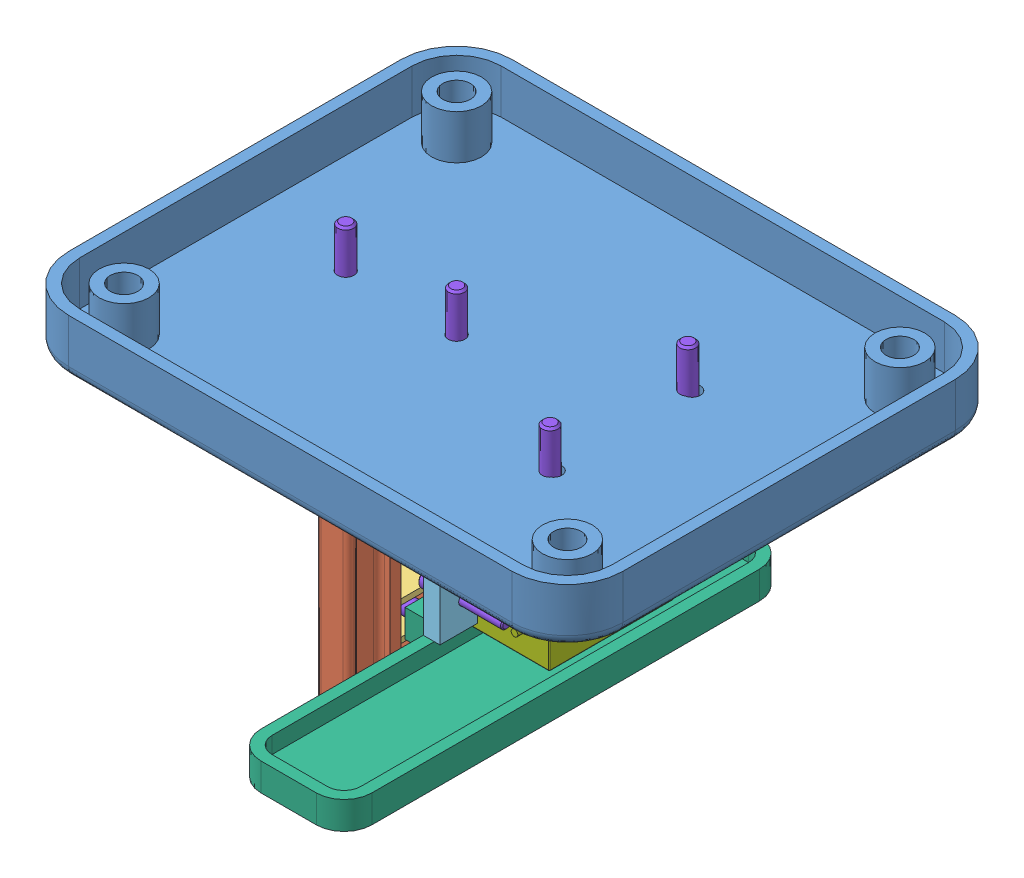
SolidWorks assembly Motion study assembly, configuration Default. Lengths in mm.
Overall size (100 83 80).
14 component instances, 8 part files, 34 mates.
Components (placement in the parent):
- Base-1: Base [Default] at (51.918 74.0446 50.8115) size (100 10 80)
- Bracket-1: Bracket [Default] at (31.918 74.0446 50.8115) x (-1 0 0) z (0 0 1) size (36 73 36)
- Clip-1: Clip [Default] at (26.918 29.2652 50.8115) x (0 0 1) z (0 1 0) size (10 8 7)
- Servo arm-1: Servo arm [Default] at (41.418 41.8648 42.8609) x (0 -0.880042 0.474895) z (1 0 0) size (10 38 4)
- Servo mount-1: Servo mount [Default] at (53.918 74.0446 50.8115) x (-1 0 0) z (0 1 0) size (30 36 30)
- Shelf-1: Shelf [Default] at (51.618 26.7652 50.8115) x (0 0 1) z (-1 0 0) size (80 5 26)
- Micro Servo FS90R Continuous-1: Micro Servo FS90R Continuous [Valor predeterminado] at (53.918 48.9882 50.8115) x (0 0 -1) z (0 1 0) size (32 29 12)
- socket head cap screw_ai-2: socket head cap screw_ai [HX-SHCS 0.112-40x0.5x0.5-N] at (24.0732 29.2652 50.8115) x (1 0 0) z (0 -0.559451 -0.828864) size (15.54 4.65 4.65)
- socket head cap screw_ai-3: socket head cap screw_ai [HX-SHCS 0.112-40x0.5x0.5-N] at (21.918 68.1998 50.8115) x (0 1 0) z (0 0 1) size (15.54 4.65 4.65)
- socket head cap screw_ai-4: socket head cap screw_ai [HX-SHCS 0.112-40x0.5x0.5-N] at (71.3976 68.113 38.5649) x (0 1 0) z (0 0 1) size (15.54 4.65 4.65)
- socket head cap screw_ai-5: socket head cap screw_ai [HX-SHCS 0.112-40x0.5x0.5-N] at (71.6494 68.1161 63.6657) x (0 1 0) z (0 0 1) size (15.54 4.65 4.65)
- socket head cap screw_ai-6: socket head cap screw_ai [HX-SHCS 0.112-40x0.5x0.5-N] at (41.918 68.1998 50.8115) x (0 1 0) z (0 0 1) size (15.54 4.65 4.65)
- socket head cap screw_ai-9: socket head cap screw_ai [HX-SHCS 0.073-72x0.5x0.5-N] at (50.0638 48.9882 64.4365) size (14.55 3 3)
- socket head cap screw_ai-10: socket head cap screw_ai [HX-SHCS 0.073-72x0.5x0.5-N] at (50.0638 48.9882 37.1865) size (14.55 3 3)
Mates (geometry in assembly coordinates):
- Coincident1: coincident anti-aligned: plane of Base-1 through (51.918 74.0446 50.8115) normal (0 -1 0); plane of Bracket-1 through (31.918 74.0446 50.8115) normal (0 1 0)
- Concentric1: concentric anti-aligned: cylinder of Base-1 through (21.918 74.0446 50.8115) axis (0 1 0) radius 1.5; cylinder of Bracket-1 through (21.918 74.0446 50.8115) axis (0 -1 0) radius 1.5
- Concentric2: concentric anti-aligned: cylinder of Base-1 through (41.918 74.0446 50.8115) axis (0 1 0) radius 1.5; cylinder of Bracket-1 through (41.918 74.0446 50.8115) axis (0 -1 0) radius 1.5
- Coincident2: coincident anti-aligned: plane of Base-1 through (51.918 74.0446 50.8115) normal (0 -1 0); plane of Servo mount-1 through (53.918 74.0446 68.8115) normal (0 1 0)
- Concentric3: concentric anti-aligned: circle of Base-1; circle of Servo mount-1
- Concentric4: concentric anti-aligned: circle of Base-1; circle of Servo mount-1
- Parallel1: parallel anti-aligned: plane of Bracket-1 through (31.918 71.0446 50.8115) normal (0 -1 0); plane of Clip-1 through (28.918 32.7652 55.8115) normal (0 1 0)
- Coincident6: coincident anti-aligned: plane of Bracket-1 through (13.918 11.0446 47.8115) normal (0 0 1); plane of Clip-1 through (34.918 26.7652 47.8115) normal (0 0 -1)
- Concentric5: concentric anti-aligned: circle of Clip-1; circle of Shelf-1
- Coincident8: coincident anti-aligned: plane of Clip-1 through (34.918 26.7652 53.8115) normal (0 1 0); plane of Shelf-1 through (51.618 26.7652 50.8115) normal (0 -1 0)
- Coincident9: coincident anti-aligned: plane of Clip-1 through (34.918 31.7652 53.8115) normal (0 -1 0); plane of Shelf-1 through (51.618 31.7652 50.8115) normal (0 1 0)
- Concentric6: concentric anti-aligned: cylinder of Servo mount-1 through (83.918 48.9882 37.1865) axis (-1 0 0) radius 1; cylinder of Micro Servo FS90R Continuous-1 through (51.918 48.9882 37.1865) axis (1 0 0) radius 1
- Concentric7: concentric anti-aligned: cylinder of Servo mount-1 through (83.918 48.9882 64.4365) axis (-1 0 0) radius 1; cylinder of Micro Servo FS90R Continuous-1 through (51.918 48.9882 64.4365) axis (1 0 0) radius 1
- Coincident11: coincident anti-aligned: plane of Servo mount-1 through (83.918 56.0446 62.0615) normal (0 0 -1); plane of Micro Servo FS90R Continuous-1 through (69.918 42.9882 62.0615) normal (0 0 1)
- Coincident12: coincident anti-aligned: plane of Servo mount-1 through (53.918 44.0446 68.8115) normal (-1 0 0); plane of Micro Servo FS90R Continuous-1 through (53.918 48.9882 37.1865) normal (1 0 0)
- Concentric8: concentric anti-aligned: cylinder of Servo arm-1 through (43.418 48.9882 56.0615) axis (-1 0 0) radius 2.25; cylinder of Micro Servo FS90R Continuous-1 through (40.918 48.9882 56.0615) axis (1 0 0) radius 2.25
- Coincident13: coincident anti-aligned: plane of Servo arm-1 through (43.418 48.9882 56.0615) normal (1 0 0); plane of Micro Servo FS90R Continuous-1 through (43.418 48.9882 56.0615) normal (-1 0 0)
- Concentric9: concentric anti-aligned: cylinder of Clip-1 through (26.918 29.2652 50.8115) axis (1 0 0) radius 1.425; cylinder of socket head cap screw_ai-2 through (-7.6768 29.2652 50.8115) axis (-1 0 0) radius 2.3241
- Coincident14: coincident anti-aligned: plane of Clip-1 through (26.918 29.2652 50.8115) normal (-1 0 0); plane of socket head cap screw_ai-2 through (26.918 27.3389 52.1117) normal (1 0 0)
- Concentric10: concentric aligned: cylinder of Bracket-1 through (21.918 74.0446 50.8115) axis (0 -1 0) radius 1.5; cylinder of socket head cap screw_ai-3 through (21.918 36.4498 50.8115) axis (0 -1 0) radius 2.3241
- Coincident15: coincident anti-aligned: plane of Bracket-1 through (31.918 71.0446 50.8115) normal (0 -1 0); plane of socket head cap screw_ai-3 through (19.5939 71.0446 50.8115) normal (0 1 0)
- Concentric11: concentric aligned: cylinder of Bracket-1 through (41.918 74.0446 50.8115) axis (0 -1 0) radius 1.5; cylinder of socket head cap screw_ai-6 through (41.918 36.4498 50.8115) axis (0 -1 0) radius 2.3241
- Coincident16: coincident anti-aligned: plane of Bracket-1 through (31.918 71.0446 50.8115) normal (0 -1 0); plane of socket head cap screw_ai-6 through (39.5939 71.0446 50.8115) normal (0 1 0)
- Concentric12: concentric anti-aligned: cylinder of Micro Servo FS90R Continuous-1 through (51.918 48.9882 37.1865) axis (1 0 0) radius 1; cylinder of socket head cap screw_ai-10 through (18.3138 48.9882 37.1865) axis (-1 0 0) radius 0.9271
- Coincident18: coincident anti-aligned: plane of Micro Servo FS90R Continuous-1 through (51.918 48.9882 37.1865) normal (-1 0 0); plane of socket head cap screw_ai-10 through (51.918 50.4868 37.1865) normal (1 0 0)
- Concentric13: concentric aligned: cylinder of Servo mount-1 through (83.918 48.9882 64.4365) axis (-1 0 0) radius 1; cylinder of socket head cap screw_ai-9 through (18.3138 48.9882 64.4365) axis (-1 0 0) radius 0.9271
- Coincident19: coincident anti-aligned: plane of Micro Servo FS90R Continuous-1 through (51.918 48.9882 64.4365) normal (-1 0 0); plane of socket head cap screw_ai-9 through (51.918 50.4868 64.4365) normal (1 0 0)
- Coincident20: coincident anti-aligned: plane of Shelf-1 through (39.618 29.2652 50.8115) normal (-1 0 0); plane of socket head cap screw_ai-2 through (39.618 28.3999 51.3956) normal (1 0 0)
- Parallel2: parallel anti-aligned: plane of Bracket-1 through (30.918 9.0446 46.3115) normal (-1 0 0); plane of Clip-1 through (28.918 29.2652 50.8115) normal (1 0 0)
- Coincident22: coincident anti-aligned: plane of Bracket-1 through (28.918 46.0446 50.8115) normal (-1 0 0); plane of Clip-1 through (28.918 29.2652 50.8115) normal (1 0 0)
- Coincident23: coincident anti-aligned: plane of Servo mount-1 through (53.918 71.0446 68.8115) normal (0 -1 0); plane of socket head cap screw_ai-5 through (69.5939 71.0446 63.3115) normal (0 1 0)
- Coincident24: coincident anti-aligned: plane of Servo mount-1 through (53.918 71.0446 68.8115) normal (0 -1 0); plane of socket head cap screw_ai-4 through (69.5939 71.0446 38.3115) normal (0 1 0)
- Concentric14: concentric aligned: cylinder of Servo mount-1 through (71.918 74.0446 38.3115) axis (0 -1 0) radius 1.5; cylinder of socket head cap screw_ai-4 through (71.918 36.4498 38.3115) axis (0 -1 0) radius 1.4224
- Concentric15: concentric aligned: cylinder of Servo mount-1 through (71.918 74.0446 63.3115) axis (0 -1 0) radius 1.5; cylinder of socket head cap screw_ai-5 through (71.918 36.4498 63.3115) axis (0 -1 0) radius 1.4224
